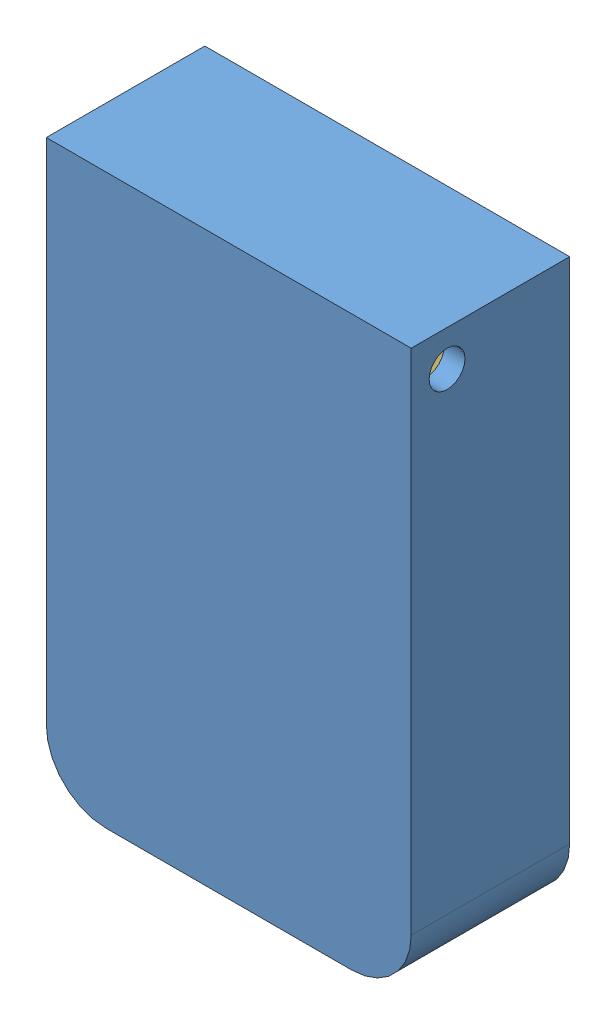
SolidWorks assembly Assem1, configuration Default. Lengths in mm.
Overall size (61 95 26.5).
3 component instances, 3 part files, 5 mates.
Components (placement in the parent):
- case_in_cable-1: case_in_cable [Default] at (-28.2681 28.8188 -17.1624) size (61 95 26.5)
- platine-1: platine [Default] at (0.2319 53.8188 0.7376) x (0 -1 0) z (0 0 -1) size (69.02 57 18)
- case_in_cable_top-1: case_in_cable_top [Default] at (-28.2698 26.6927 -18.6624) x (0.000045 -1 0) z (0 0 1) size (92.25 59 5.5)
Mates (geometry in assembly coordinates):
- Concentric2: concentric aligned: circle of case_in_cable-1; circle of platine-1
- Concentric3: concentric aligned: circle of case_in_cable-1; circle of platine-1
- Concentric4: concentric anti-aligned: circle of case_in_cable-1; circle of case_in_cable_top-1
- Coincident1: coincident anti-aligned: plane of case_in_cable-1 through (-28.2681 28.8188 -17.1624) normal (0 0 -1); plane of case_in_cable_top-1 through (-47.7682 -7.6831 -17.1624) normal (0 0 1)
- Coincident3: coincident anti-aligned: plane of case_in_cable-1 through (-6.7681 40.8188 2.3376) normal (0 0 -1); plane of platine-1 through (0.2319 53.8188 2.3376) normal (0 0 1)
